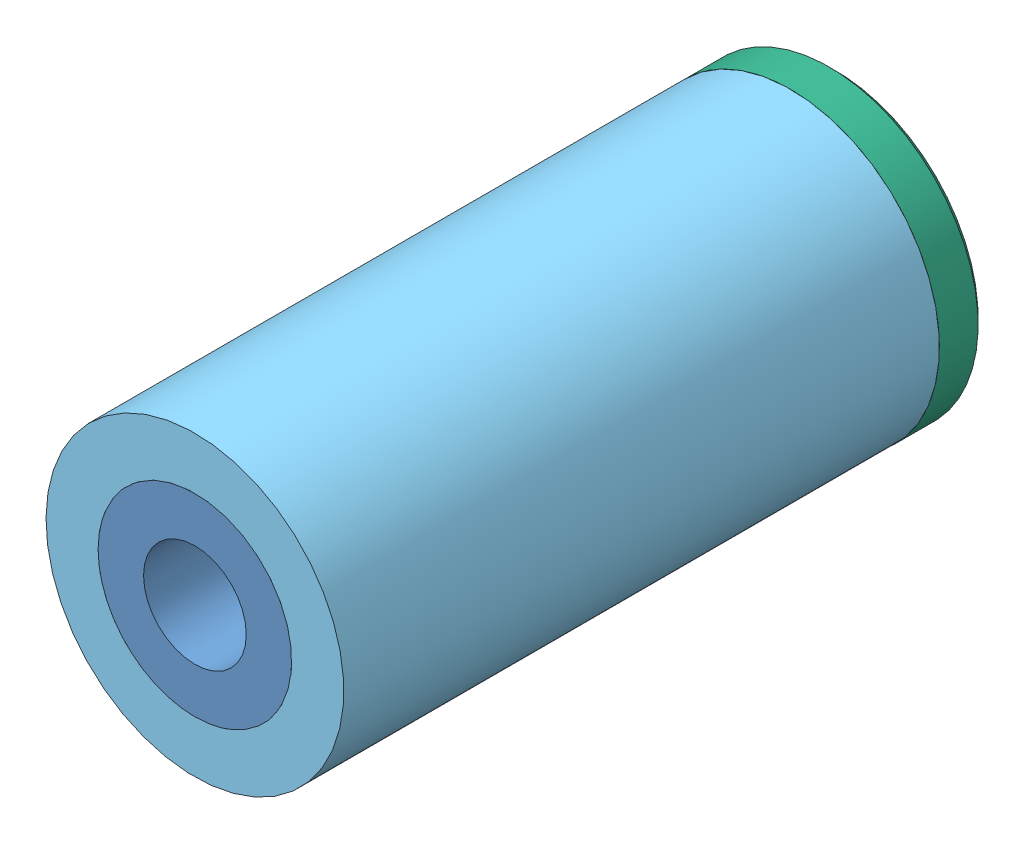
SolidWorks assembly Sensor_montiert, configuration Standard. Lengths in mm.
Overall size (132.51 132.51 214.99).
11 component instances, 7 part files, 9 mates.
Components (placement in the parent):
- Rohr-1: Rohr [Standard] at (-3.8058 3.5793 150) x (0 0 -1) z (1 0 0) size (100 65 65)
- LED_Zapfen-1: LED_Zapfen [Standard] at (-3.8058 37.8293 100) x (0 -1 0) z (-0.788966 0 0.614436) size (17 16 16)
- Detector-1: Detector [Standard] at (-32.2013 -12.8943 104.3389) x (1 0 0) z (0 0.981422 -0.191863) size (17 16 16)
  - Detector_Zapfen-1: Detector_Zapfen [Standard] at (-5.8545 1.0976 17) size (17 16 16)
  - Detector_rückenteil-1: Detector_rückenteil [Standard] at (-0.2545 1.0976 17) x (0 0.350017 -0.936743) z (1 0 0) size (10 8 5.6)
- Detector-2: Detector [Standard] at (24.5897 1.5411 116.913) x (-1 0 0) z (0 0.055425 -0.998463) size (17 16 16)
  - Detector_Zapfen-1: Detector_Zapfen [Standard] at (-5.8545 1.0976 17) size (17 16 16)
  - Detector_rückenteil-1: Detector_rückenteil [Standard] at (-0.2545 1.0976 17) x (0 0.350017 -0.936743) z (1 0 0) size (10 8 5.6)
- Aussenhülle-1: Aussenhülle [Standard] at (-3.8058 3.5793 150) x (0 0 -1) z (0.996537 -0.083148 0) size (200 100 100)
- Deckel-1: Deckel [Standard] at (-3.8058 3.5793 -64.9852) x (0 0 1) z (-0.415508 -0.909589 0) size (30 100 100)
- Print-1: Print [Standard] at (-2.0357 3.9405 7.098) x (0 0 1) z (1 0 0) size (80 60 2)
Mates (geometry in assembly coordinates):
- Konzentrisch1: concentric aligned: cylinder of Rohr-1 through (-3.8058 26.3293 100) axis (0 1 0) radius 8; cylinder of LED_Zapfen-1 through (-3.8058 37.8293 100) axis (0 1 0) radius 8
- Deckungsgleich1: coincident anti-aligned: plane of Rohr-1 through (-3.8058 26.3293 100) normal (0 1 0); plane of LED_Zapfen-1 through (-0.7336 26.3293 103.9448) normal (0 -1 0)
- Konzentrisch2: concentric aligned: cylinder of Rohr-1 through (-26.5558 3.5793 100) axis (-1 0 0) radius 8; cylinder of Detector-1/Detector_Zapfen-1 through (-38.0558 3.5793 100) axis (-1 0 0) radius 8
- Deckungsgleich2: coincident anti-aligned: plane of Rohr-1 through (-26.5558 3.5793 100) normal (-1 0 0); plane of Detector-1/Detector_Zapfen-1 through (-26.5558 2.62 95.0929) normal (1 0 0)
- Konzentrisch3: concentric aligned: cylinder of Rohr-1 through (18.9442 3.5793 100) axis (1 0 0) radius 8; cylinder of Detector-2/Detector_Zapfen-1 through (30.4442 3.5793 100) axis (1 0 0) radius 8
- Deckungsgleich3: coincident anti-aligned: plane of Rohr-1 through (18.9442 3.5793 100) normal (1 0 0); plane of Detector-2/Detector_Zapfen-1 through (18.9442 8.5716 100.2771) normal (-1 0 0)
- Konzentrisch4: concentric aligned: cylinder of Rohr-1 through (-3.8058 3.5793 150) axis (0 0 1) radius 32.5; cylinder of Aussenhülle-1 through (-3.8058 3.5793 150) axis (0 0 1) radius 32.5
- Konzentrisch5: concentric anti-aligned: cylinder of Aussenhülle-1 through (-3.8058 3.5793 150) axis (0 0 1) radius 40; cylinder of Deckel-1 through (-3.8058 3.5793 -64.9852) axis (0 0 -1) radius 40
- Deckungsgleich4: coincident aligned: plane of Rohr-1 through (-3.8058 20.8293 150) normal (0 0 1); plane of Aussenhülle-1 through (0.3516 53.4061 150) normal (0 0 1)
